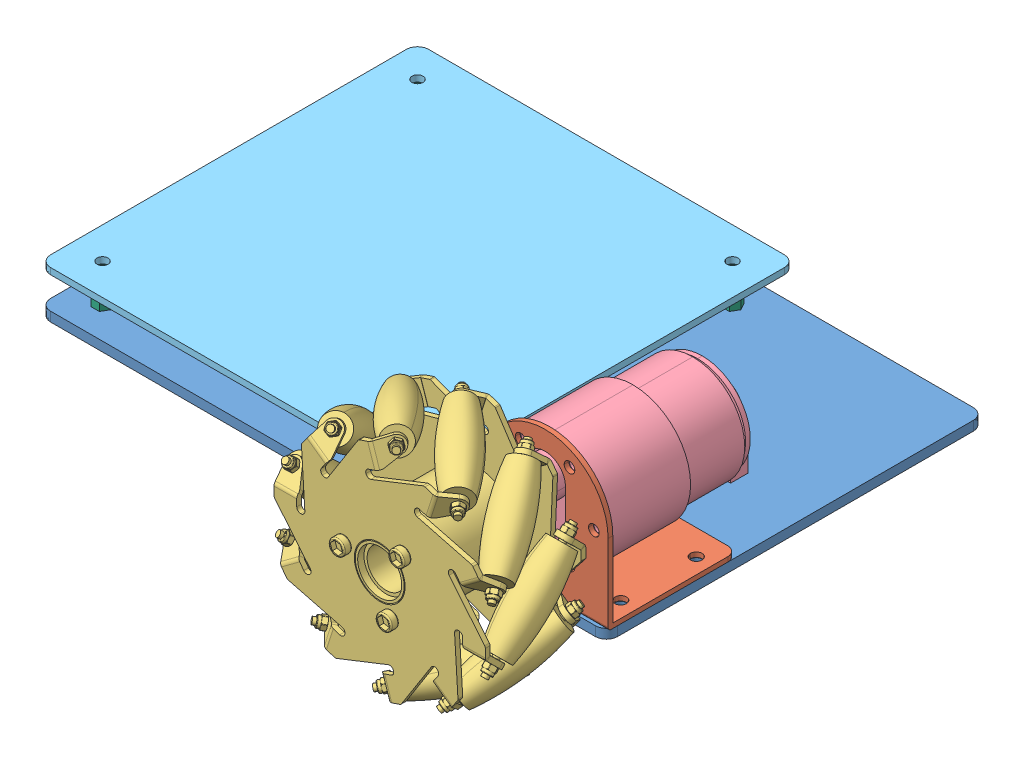
SolidWorks assembly 装配体, configuration 默认. Lengths in mm.
Overall size (224.73 131.98 176.29).
9 component instances, 6 part files, 19 mates.
Components (placement in the parent):
- 载物底板-1: 载物底板 [默认] at (-123.9712 15.4284 -40) size (180 3 120)
- 37电机支架-1: 37电机支架 [默认] at (16.0288 18.4284 79.5) x (0 0 -1) z (1 0 0) size (41 45.5 40)
- 75mm麦轮-1: 75mm麦轮 [默认] at (36.0288 50.9284 101.5) x (-0.317176 0.948367 0) z (0.948367 0.317176 0) size (105.29 52.3 101.3)
- mg513-30F_电机-1: mg513-30F_电机 [默认] at (36.0288 43.9284 78) x (0 -1 0) z (1 0 0) size (36.6 73.4 36.6)
- PCB板-1: PCB板 [默认] at (-63.9712 28.4284 20) size (120 2 120)
- 铜柱-1: 铜柱 [默认] at (-13.9712 18.4284 70) size (5.43 10 4.7)
- 铜柱-2: 铜柱 [默认] at (-13.9712 18.4284 -30) size (5.43 10 4.7)
- 铜柱-3: 铜柱 [默认] at (-113.9712 18.4284 70) size (5.43 10 4.7)
- 铜柱-4: 铜柱 [默认] at (-113.9712 18.4284 -30) size (5.43 10 4.7)
Mates (geometry in assembly coordinates):
- 同心1: concentric: cylinder of assembly; cylinder of assembly; cylinder of 载物底板-1 through (51.0288 15.4284 70.5) axis (0 1 0) radius 1.75; cylinder of 37电机支架-1 through (51.0288 18.4284 70.5) axis (0 -1 0) radius 1.85
- 同心2: concentric: cylinder of assembly; cylinder of assembly; cylinder of 载物底板-1 through (21.0288 15.4284 46.5) axis (0 1 0) radius 1.75; cylinder of 37电机支架-1 through (21.0288 18.4284 46.5) axis (0 -1 0) radius 1.85
- 重合1: coincident: plane of assembly; plane of assembly; plane of 37电机支架-1 through (56.0288 19.9284 78) normal (0 0 -1); plane of mg513-30F_电机-1 through (36.0288 43.9284 78) normal (0 0 1)
- 同心3: concentric: cylinder of assembly; cylinder of assembly; cylinder of 37电机支架-1 through (43.7788 57.3518 79.5) axis (0 0 1) radius 1.7; cylinder of mg513-30F_电机-1 through (43.7788 57.3518 78) axis (0 0 1) radius 1.5
- 同心4: concentric: cylinder of assembly; cylinder of assembly; cylinder of 37电机支架-1 through (28.2788 57.3518 79.5) axis (0 0 1) radius 1.7; cylinder of mg513-30F_电机-1 through (28.2788 57.3518 78) axis (0 0 1) radius 1.5
- 重合2: coincident: plane of assembly; plane of assembly; plane of 载物底板-1 through (-123.9712 18.4284 -40) normal (0 1 0); plane of 37电机支架-1 through (16.0288 18.4284 38.5) normal (0 -1 0)
- 相切3: tangent: plane of assembly; face of 75mm麦轮-1; plane of mg513-30F_电机-1 through (36.0288 43.9284 84) normal (0 0 1)
- 相切7: tangent: cylinder of assembly; face of 75mm麦轮-1; cylinder of mg513-30F_电机-1 through (36.0288 50.9284 78) axis (0 0 1) radius 6
- 同心5: concentric: cylinder of 载物底板-1 through (-113.9712 15.4284 -30) axis (0 1 0) radius 1.75; cylinder of ? through (-113.9712 86.6631 -30) axis (0 1 0) radius 1.75
- 同心6: concentric: cylinder of 载物底板-1 through (-13.9712 15.4284 70) axis (0 1 0) radius 1.75; cylinder of ? through (-13.9712 86.6631 70) axis (0 1 0) radius 1.75
- 重合3: coincident: plane of ? through (-63.9712 86.6631 20) normal (0 -1 0); plane of ? through (-13.9712 86.6631 -30) normal (0 1 0)
- 同心7: concentric: cylinder of ? through (-13.9712 86.6631 -30) axis (0 1 0) radius 1.75; cylinder of ? through (-13.9712 76.6631 -30) axis (0 1 0) radius 1.5
- 重合5: coincident: plane of ? through (-63.9712 86.6631 20) normal (0 -1 0); plane of ? through (-13.9712 86.6631 70) normal (0 1 0)
- 同心8: concentric: cylinder of ? through (-13.9712 86.6631 70) axis (0 1 0) radius 1.75; cylinder of ? through (-13.9712 76.6631 70) axis (0 1 0) radius 1.5
- 重合6: coincident: plane of ? through (-63.9712 86.6631 20) normal (0 -1 0); plane of ? through (-113.9712 86.6631 -30) normal (0 1 0)
- 同心9: concentric: cylinder of ? through (-113.9712 86.6631 -30) axis (0 1 0) radius 1.75; cylinder of ? through (-113.9712 76.6631 -30) axis (0 1 0) radius 1.5
- 重合7: coincident: plane of ? through (-63.9712 86.6631 20) normal (0 -1 0); plane of ? through (-113.9712 86.6631 70) normal (0 1 0)
- 同心11: concentric: cylinder of ? through (-113.9712 86.6631 70) axis (0 1 0) radius 1.75; cylinder of ? through (-113.9712 76.6631 70) axis (0 1 0) radius 1.5
- 重合8: coincident: plane of assembly; plane of assembly; plane of 载物底板-1 through (-123.9712 18.4284 -40) normal (0 1 0); plane of 铜柱-2 through (-13.9712 18.4284 -30) normal (0 -1 0)
